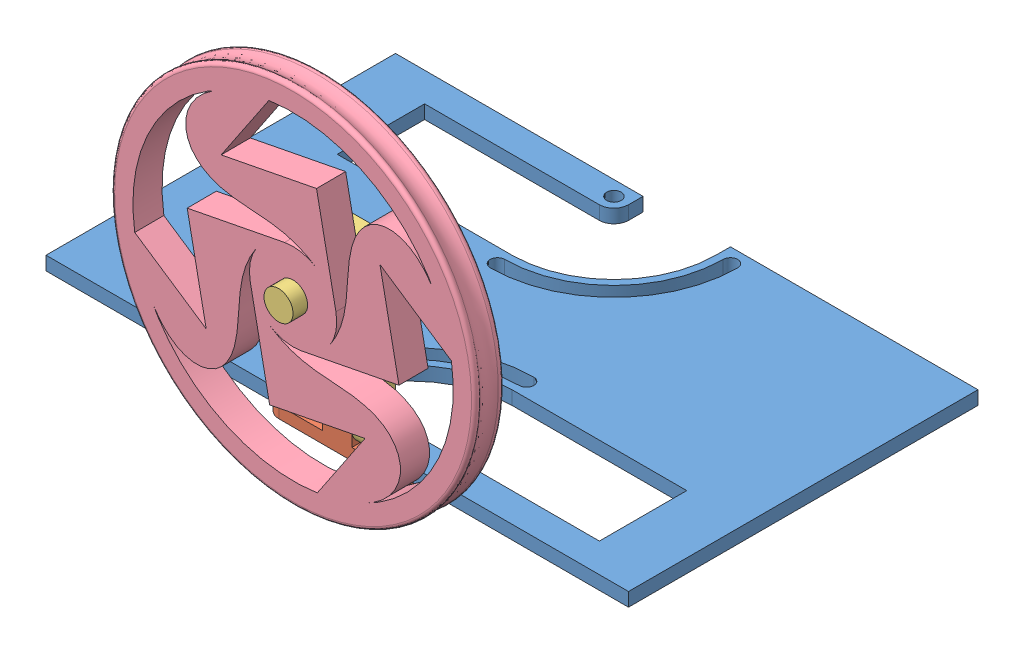
SolidWorks assembly Assembly, configuration Default. Lengths in mm.
Overall size (127 110.2 89.03).
4 component instances, 4 part files, 7 mates.
Components (placement in the parent):
- Chassis-1: Chassis [Default] at (19.9161 58.415 83.8245) size (127 2.97 76.2)
- Truck-1: Truck [Default] at (19.9161 58.415 118.7495) x (1 0 0) z (0 0 -1) size (31.75 8.89 6.35)
- Wheel Standoff-1: Wheel Standoff [Default] at (19.9161 58.4268 115.5628) x (1 0 0) z (0 -0.003716 0.999993) size (12.7 38.1 19.05)
- Wheel-1: Wheel [Default] at (19.9161 90.1294 128.3806) x (0.829587 -0.558374 -0.002075) z (0 -0.003716 0.999993) size (79.38 79.38 6.35)
Mates (geometry in assembly coordinates):
- Concentric1: concentric anti-aligned: cylinder of Chassis-1 through (32.6161 58.415 118.7495) axis (0 1 0) radius 1.5875; cylinder of Truck-1 through (32.6161 61.3868 118.7495) axis (0 -1 0) radius 1.5875
- Coincident1: coincident anti-aligned: plane of Chassis-1 through (19.9161 58.415 83.8245) normal (0 -1 0); plane of Truck-1 through (7.2161 58.415 118.7495) normal (0 1 0)
- Slot1: slot anti-aligned: cylinder of Truck-1 through (7.2161 61.3868 118.7495) axis (0 -1 0) radius 1.5875; cylinder of Chassis-1 through (32.6161 58.415 118.7495) axis (0 1 0) radius 26.9875; cylinder of Chassis-1 through (32.6161 58.415 93.3495) axis (0 1 0) radius 1.5875
- Concentric2: concentric aligned: cylinder of Truck-1 through (16.7411 61.59 118.7495) axis (1 0 0) radius 1.5875; cylinder of Wheel Standoff-1 through (13.5661 61.59 118.7495) axis (1 0 0) radius 1.5875
- Coincident2: coincident anti-aligned: plane of Truck-1 through (16.7411 64.765 121.9245) normal (-1 0 0); plane of Wheel Standoff-1 through (16.7411 58.4032 121.9127) normal (1 0 0)
- Concentric3: concentric aligned: cylinder of Wheel Standoff-1 through (19.9161 90.1058 134.7306) axis (0 0.003716 -0.999993) radius 3.175; cylinder of Wheel-1 through (19.9161 90.1424 124.8882) axis (0 0.003716 -0.999993) radius 3.175
- Distance1: distance = 3.175 mm aligned: plane of Wheel Standoff-1 through (19.9161 90.1058 134.7306) normal (0 -0.003716 0.999993); plane of Wheel-1 through (21.689 92.7515 131.5654) normal (0 -0.003716 0.999993)
